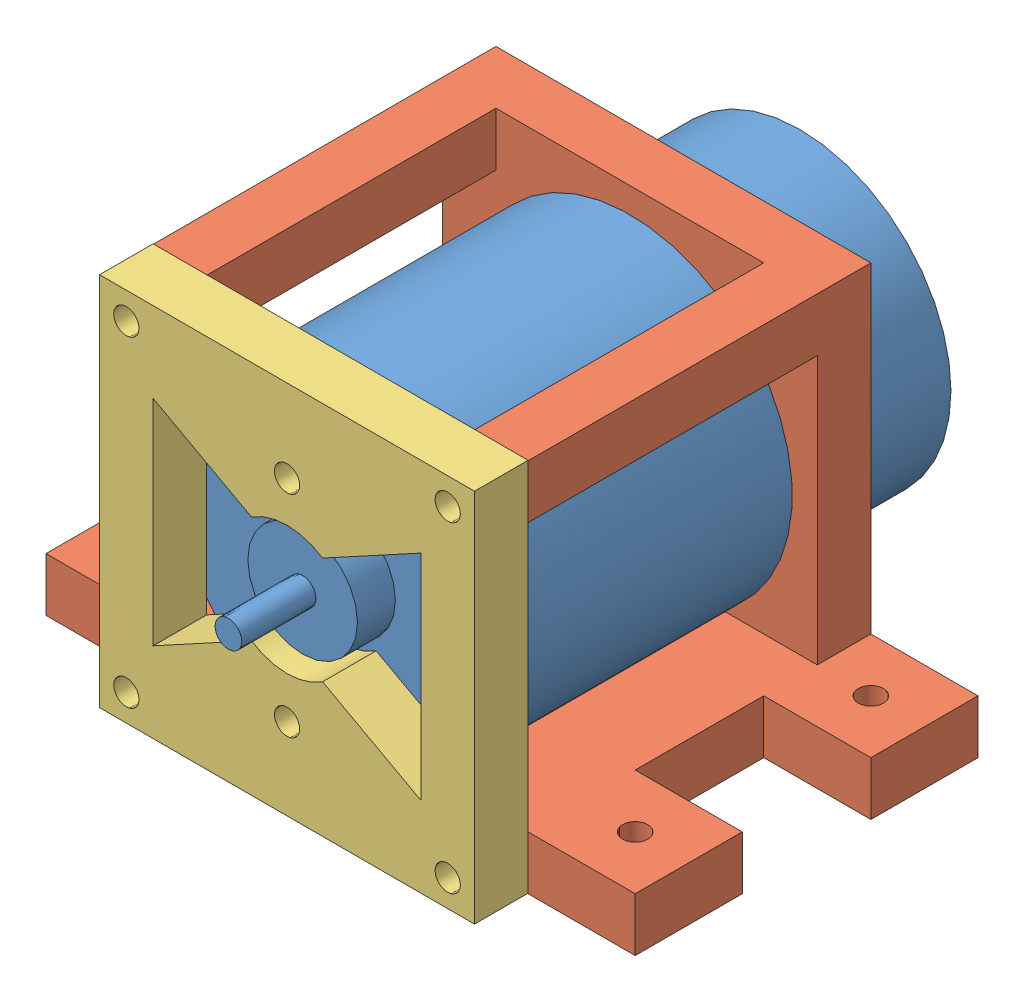
SolidWorks assembly Motor Mount, configuration Default. Lengths in mm.
Overall size (69.85 44.5 73.76).
3 component instances, 3 part files, 7 mates.
Components (placement in the parent):
- Motor-1: Motor [Default] at (21.4622 40.8203 40.5186) size (38.5 38.5 73.76)
- Mount-1: Mount [Default] at (-0.7628 18.5953 41.1786) x (0 0 1) z (-1 0 0) size (40.64 44.45 69.85)
- Top-1: Top [Default] at (-0.7628 18.6493 81.8186) size (44.45 44.45 6.35)
Mates (geometry in assembly coordinates):
- Concentric1: concentric aligned: cylinder of Motor-1 through (21.4622 40.8203 81.8186) axis (0 0 -1) radius 19.25; cylinder of Mount-1 through (21.4622 40.8203 81.8186) axis (0 0 -1) radius 19.05
- Concentric2: concentric aligned: cylinder of Motor-1 through (21.4622 53.3203 78.8186) axis (0 0 1) radius 1.6; circle of Top-1
- Concentric7: concentric aligned: cylinder of Motor-1 through (21.4622 28.3203 78.8186) axis (0 0 1) radius 1.6; cylinder of Top-1 through (21.4622 28.3203 81.8186) axis (0 0 1) radius 1.5
- Coincident1: coincident anti-aligned: plane of Motor-1 through (21.4622 40.8203 81.8186) normal (0 0 1); plane of Top-1 through (-0.7628 18.6493 81.8186) normal (0 0 -1)
- Parallel2: parallel aligned: cylinder of Mount-1 through (2.4122 59.8703 75.4686) axis (0 0 1) radius 1.5; cylinder of Top-1 through (2.4122 59.9243 81.8186) axis (0 0 1) radius 1.5
- Coincident2: coincident anti-aligned: plane of Mount-1 through (-0.7628 18.5953 81.8186) normal (0 0 1); plane of Top-1 through (-0.7628 18.6493 81.8186) normal (0 0 -1)
- Parallel3: parallel aligned: cylinder of Mount-1 through (2.4122 21.7703 75.4686) axis (0 0 1) radius 1.5; cylinder of Top-1 through (2.4122 21.8243 81.8186) axis (0 0 1) radius 1.5
